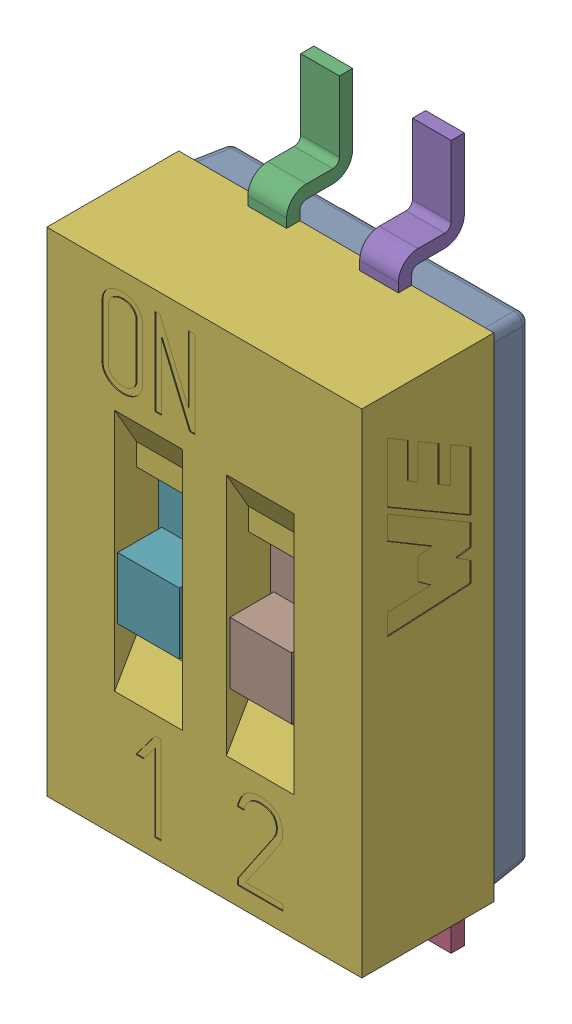
SolidWorks assembly 416131160802, configuration Default. Lengths in mm.
Overall size (3.58 8 2.1).
8 component instances, 5 part files, 0 mates.
Components (placement in the parent):
- base_2-1: base_2 [Default] at origin size (3.48 5.5 0.65)
- pins-1: pins [Default] at (-0.635 0 0) size (1 3.75 0.75)
- pins_2-1: pins_2 [Default] at (-0.635 0 0) size (1 2.85 0.75)
- pins-2: pins [Default] at (0.635 0 0) size (1 3.75 0.75)
- pins_2-2: pins_2 [Default] at (0.635 0 0) size (1 2.85 0.75)
- cap-1: cap [Default] at origin size (3.58 5.6 1.5)
- clip-1: clip [Default] at (-0.635 0 0) size (1 2.6 0.95)
- clip-2: clip [Default] at (0.64 0 0) size (1 2.6 0.95)
